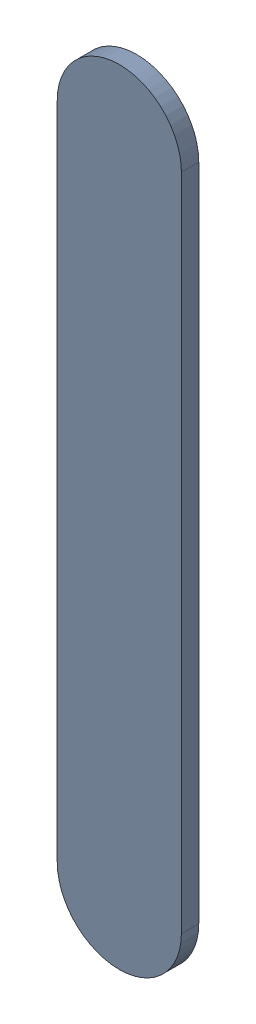
SolidWorks assembly Track (26.95mm,41.5mm)(26.95mm,42.85mm) on Top Layer, configuration Predeterminado. Lengths in mm.
Overall size (0.25 1.6 0.04).
2 component instances, 1 part files, 0 mates.
Components (placement in the parent):
- Track (26.95mm,41.5mm)(26.95mm,42.85mm) on Top Layer-1-1: Track (26.95mm,41.5mm)(26.95mm,42.85mm) on Top Layer-1 [Predeterminado] at (-68.317 -44.187 -0.0457) size (0.25 1.6 0.04)
  - Track (26.95mm,41.5mm)(26.95mm,42.85mm) on Top Layer-Part-1-1: Track (26.95mm,41.5mm)(26.95mm,42.85mm) on Top Layer-Part-1 [Predeterminado] at origin size (0.25 1.6 0.04)
